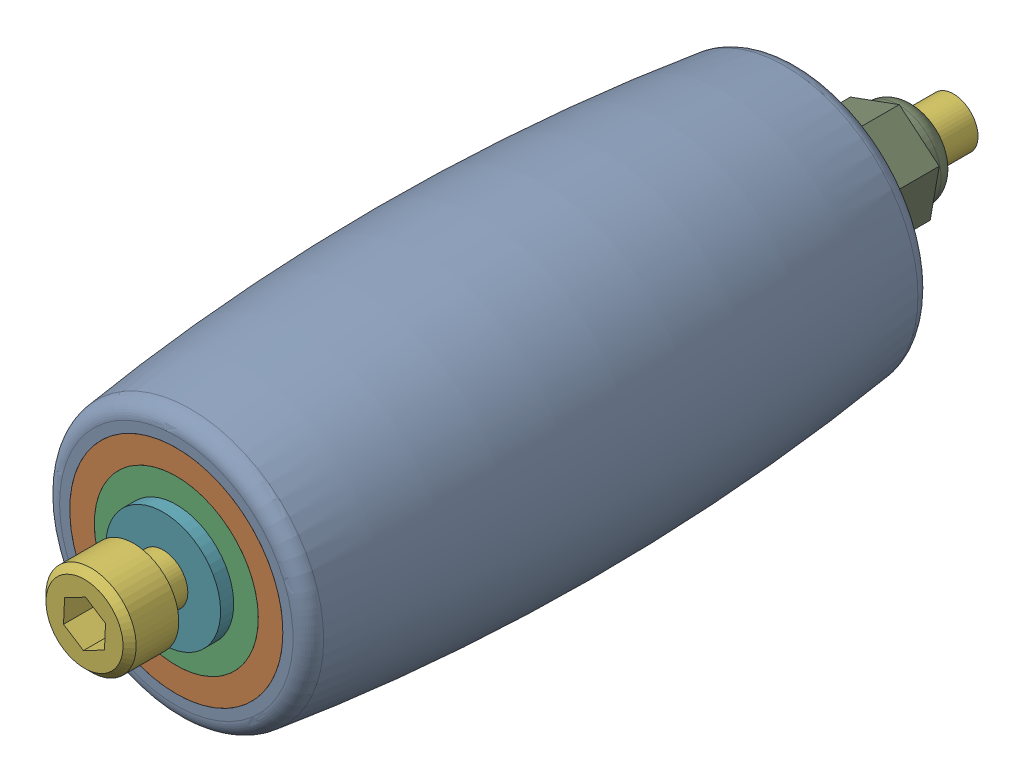
SolidWorks assembly 滚花橡胶轮组装（5）, configuration 默认. Lengths in mm.
Overall size (18.5 18.5 53).
9 component instances, 7 part files, 16 mates.
Components (placement in the parent):
- 滚花橡胶轮外（5）-1: 滚花橡胶轮外（5） [默认] at (-9.896 1.7835 38.5971) size (18.5 18.5 38)
- 滚花铝柱（5）-1: 滚花铝柱（5） [默认] at (-9.896 1.7835 38) x (0.787441 0.61639 0) z (-0.61639 0.787441 0) size (13 38 13)
- 轴承5X10X4（5）-1: 轴承5X10X4（5） [默认] at (-9.896 1.7835 55) x (0.442498 0.896769 0) z (-0.896769 0.442498 0) size (10 4 10)
- 轴承5X10X4（5）-2: 轴承5X10X4（5） [默认] at (-9.896 1.7835 21) x (0.442498 0.896769 0) z (-0.896769 0.442498 0) size (10 4 10)
- 铜管3X5（5）-1: 铜管3X5（5） [默认] at (-9.896 1.7835 38) x (0.823254 0.567673 0) z (-0.567673 0.823254 0) size (5 38 5)
- 螺丝（5）-1: 螺丝（5） [默认] at (-9.896 1.7835 59.6) x (-0.462621 0.886556 0) z (0 0 1) size (5.5 5.5 53)
- 垫片（5）-1: 垫片（5） [默认] at (-9.896 1.7835 57) x (1 0 0) z (0 -1 0) size (7 0.8 7)
- 垫片（5）-2: 垫片（5） [默认] at (-9.896 1.7835 19) x (0.746862 -0.664979 0) z (0.664979 0.746862 0) size (7 0.8 7)
- 螺母（5）-1: 螺母（5） [默认] at (-9.896 1.7835 16.2) x (-0.766894 0.641774 0) z (0 0 -1) size (6.35 5.5 4.25)
Mates (geometry in assembly coordinates):
- 重合1: coincident anti-aligned: axis of 滚花橡胶轮外（5）-1 through (-9.896 1.7835 46.941) axis (0 0 -1); axis of 滚花铝柱（5）-1 through (-9.896 1.7835 23) axis (0 0 1)
- 重合2: coincident aligned: plane of 滚花橡胶轮外（5）-1 through (-3.396 1.7835 57) normal (0 0 1); plane of 滚花铝柱（5）-1 through (-9.896 1.7835 57) normal (0 0 1)
- 同心1: concentric aligned: cylinder of 滚花铝柱（5）-1 through (-9.896 1.7835 19) axis (0 0 1) radius 2.5; cylinder of 轴承5X10X4（5）-1 through (-9.896 1.7835 53) axis (0 0 1) radius 2.5
- 重合3: coincident aligned: plane of 滚花铝柱（5）-1 through (-9.896 1.7835 57) normal (0 0 1); plane of 轴承5X10X4（5）-1 through (-9.896 1.7835 57) normal (0 0 1)
- 同心2: concentric anti-aligned: cylinder of 滚花铝柱（5）-1 through (-9.896 1.7835 23) axis (0 0 -1) radius 5; cylinder of 轴承5X10X4（5）-2 through (-9.896 1.7835 19) axis (0 0 1) radius 2.5
- 重合4: coincident aligned: plane of 滚花铝柱（5）-1 through (-9.896 1.7835 19) normal (0 0 -1); plane of 轴承5X10X4（5）-2 through (-9.896 1.7835 19) normal (0 0 -1)
- 同心3: concentric aligned: cylinder of 轴承5X10X4（5）-1 through (-9.896 1.7835 53) axis (0 0 1) radius 2.5; cylinder of 铜管3X5（5）-1 through (-9.896 1.7835 19) axis (0 0 1) radius 1.5
- 重合6: coincident aligned: plane of 轴承5X10X4（5）-2 through (-9.896 1.7835 19) normal (0 0 -1); plane of 铜管3X5（5）-1 through (-9.896 1.7835 19) normal (0 0 -1)
- 同心4: concentric aligned: cylinder of 铜管3X5（5）-1 through (-9.896 1.7835 19) axis (0 0 1) radius 1.5; cylinder of 螺丝（5）-1 through (-9.896 1.7835 9.6) axis (0 0 1) radius 1.5
- 距离1: distance = 2.6 mm anti-aligned: plane of 螺丝（5）-1 through (-11.1682 4.2215 59.6) normal (0 0 -1); plane of 轴承5X10X4（5）-1 through (-9.896 1.7835 57) normal (0 0 1)
- 同心5: concentric anti-aligned: cylinder of 螺丝（5）-1 through (-9.896 1.7835 9.6) axis (0 0 1) radius 1.5; cylinder of 垫片（5）-1 through (-9.896 1.7835 57.8) axis (0 0 -1) radius 1.5
- 重合8: coincident anti-aligned: plane of 轴承5X10X4（5）-1 through (-9.896 1.7835 57) normal (0 0 1); plane of 垫片（5）-1 through (-9.896 1.7835 57) normal (0 0 -1)
- 同心61: concentric aligned: axis of 螺丝（5）-1 through (-9.896 1.7835 9.6) axis (0 0 1); cylinder of 垫片（5）-2 through (-9.896 1.7835 18.2) axis (0 0 1) radius 3.5
- 重合9: coincident anti-aligned: plane of 轴承5X10X4（5）-2 through (-9.896 1.7835 19) normal (0 0 -1); plane of 垫片（5）-2 through (-9.896 1.7835 19) normal (0 0 1)
- 同心7: concentric aligned: cylinder of 螺丝（5）-1 through (-9.896 1.7835 9.6) axis (0 0 1) radius 1.5; cylinder of 螺母（5）-1 through (-9.896 1.7835 16.2) axis (0 0 1) radius 1.5
- 距离2: distance = 2 mm anti-aligned: plane of 螺母（5）-1 through (-9.896 1.7835 16.2) normal (0 0 1); plane of 垫片（5）-2 through (-9.896 1.7835 18.2) normal (0 0 -1)
